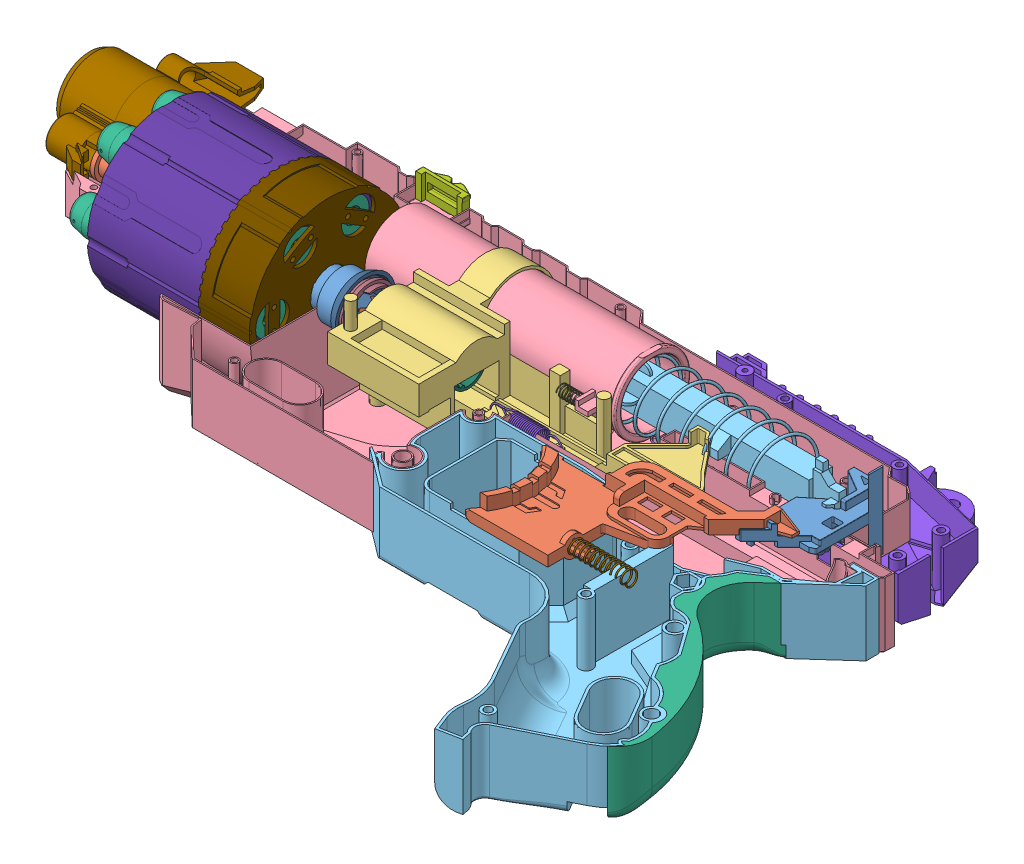
SolidWorks assembly FullAssembly, configuration Default. Lengths in mm.
Overall size (323.71 84.54 189).
50 component instances, 33 part files, 65 mates.
Components (placement in the parent):
- Casing Assembly-1: Casing Assembly [Default] at (151.4188 153.405 192.5829) size (316.26 35.4 180.45)
  - BlueCasing-1: BlueCasing [Default] at (-617.0884 -4.4748 593.468) size (308.07 35.4 103.82) (hidden)
  - Light Grey Handle-1: Light Grey Handle [Default] at (-617.0884 -4.4748 593.468) x (1 0 0) z (0 1 0) size (148.12 135.48 25.59) (hidden)
  - DarkGreyHandle-1: DarkGreyHandle [Default] at (-617.0884 -4.4748 593.468) x (1 0 0) z (0 1 0) size (51.4 89.36 25.17) (hidden)
- NerfPart1-1: NerfPart1 [Default] at (249.0248 148.9301 159.2025) x (0 0 1) z (0 1 0) size (41.76 19.13 29)
- NerfPart2-1: NerfPart2 [Default] at (217.0076 150.9301 223.4293) x (1 0 0) z (0 1 0) size (77.26 55.51 14)
- carrier assy-1: carrier assy [Default] at (183.9347 126.8386 117.2142) x (0 1 0) z (0 0 1) size (39.22 174.51 65.1)
  - Carrier-1: Carrier [Default] at (22.0915 43.5029 51.6249) size (39.22 83.08 65.1)
  - Nerf cylinder-1: Nerf cylinder [Default] at (22.0915 2.6203 51.6249) x (0 0 -1) z (0 1 0) size (34.5 28.93 100.29)
  - Piston-2: Piston [Default] at (22.0915 23.114 51.6249) x (1 0 0) z (0 -1 0) size (25 25 95)
- NerfDart-1: NerfDart [Default] at (82.2606 167.1322 185.1965) x (0 -0.202966 -0.979186) z (0 0.979186 -0.202966) size (12.8 72.8 12.8)
- Sights-1: Sights [Default] at (84.1794 153.5301 143.1658) x (-0.99995 0 -0.009952) z (0 -1 0) size (18.4 11.6 9.2)
- Slider1-1: Slider1 [Default] at (288.3635 131.9301 181.5662) x (-1 0 0) z (0 -1 0) size (112.73 46.9 27)
- Tip-1: Tip [Default] at (-6.6716 148.9301 175.5592) x (0 -1 0) z (-1 0 0) size (27.76 65.59 33.8)
- Cylinder_Rotator-1: Cylinder_Rotator [Default] at (80.8973 165.6762 224.1879) x (0 0.418707 -0.908121) z (0 -0.908121 -0.418707) size (25.03 47.62 25.04)
  - Cylinder_Rotator_pt1-1: Cylinder_Rotator_pt1 [Default] at (18.8958 8.6532 27.1526) size (23.17 32.6 23.17)
  - Cylinder_Rotator_pt2-1: Cylinder_Rotator_pt2 [Default] at (18.8958 18.6132 27.1526) x (-0.510192 0 -0.860061) z (0.860061 0 -0.510192) size (10.13 14.17 10.13)
  - Cylinder_Rotator_Spring-1: Cylinder_Rotator_Spring [Default] at (19.0112 24.4693 27.2364) size (6.17 17.01 6.17)
  - Cylinder_Rotator_Ring-1: Cylinder_Rotator_Ring [Default] at (18.8958 15.2032 27.1526) x (-0.990155 0 0.139974) z (-0.139974 0 -0.990155) size (19.4 5.35 19.23)
  - Cylinder_Rotator_Screw-1: Cylinder_Rotator_Screw [Default] at (18.8943 33.5132 27.1524) x (-0.438039 0 0.898956) z (-0.898956 0 -0.438039) size (6.55 9.42 6.55)
  - Cylinder_Rotator_pt3-1: Cylinder_Rotator_pt3 [Default] at (18.9009 56.2732 27.1494) x (-0.691686 0 -0.722198) z (-0.722198 0 0.691686) size (17.88 16.85 17.54)
  - Cylinder_Rotator_pt4-1: Cylinder_Rotator_pt4 [Default] at (18.8958 21.5032 27.1526) x (0.960127 0 0.279563) z (-0.279563 0 0.960127) size (19.34 22.93 19.73)
- CylinderAssembly-1: CylinderAssembly [Default] at (100.9463 106.9885 231.6989) x (0 -0.498348 -0.866977) z (0 0.866977 -0.498348) size (61.92 96.59 61.91)
  - Cylinder_TopHalf-1: Cylinder_TopHalf [Default] at (10.3441 36.2557 54.3227) size (61.26 74 61.24)
  - Cylinder_BottomHalf-1: Cylinder_BottomHalf [Default] at (10.3441 17.2957 54.3227) x (-0.999941 0 0.010888) z (-0.010888 0 -0.999941) size (61.26 49.19 61.25)
  - Cylinder_BottomLock-1: Cylinder_BottomLock [Default] at (10.3441 6.3257 54.3227) x (0.135612 0 0.990762) z (-0.990762 0 0.135612) size (32 44 30.63)
  - Cylinder_TopLock-1: Cylinder_TopLock [Default] at (10.3441 102.9157 54.3227) x (0.024849 0 0.999691) z (0.999691 0 -0.024849) size (12.51 52.56 12.51)
- NerfDart-2: NerfDart [Default] at (82.2606 167.0921 206.1913) x (0 -1 0) z (0 0 -1) size (12.8 72.8 12.8)
- NerfDart-3: NerfDart [Default] at (82.2606 148.8901 216.654) x (0 -1 0) z (0 0 -1) size (12.8 72.8 12.8)
- NerfDart-4: NerfDart [Default] at (82.2606 130.7681 185.1272) x (0 -0.675813 0.737073) z (0 -0.737073 -0.675813) size (12.8 72.8 12.8)
- NerfDart-5: NerfDart [Default] at (82.2606 148.9702 174.6644) x (0 -1 0) z (0 0 -1) size (12.8 72.8 12.8)
- NerfDart-6: NerfDart [Default] at (82.2606 130.7281 206.1219) x (0 -0.659658 0.751566) z (0 -0.751566 -0.659658) size (12.8 72.8 12.8)
- Slider Mirrored-1: Slider Mirrored [Default] at (288.3635 136.9301 181.5706) x (-1 0 0) z (0 -1 0) size (112.73 46.9 20.4) (hidden)
- NerfPart3-reexport-1: NerfPart3-reexport [Default] at (119.2158 139.9393 195.9682) x (1 0 0) z (0 0 -1) size (111.39 22 27.4)
- BlueCaseMirrored-1: BlueCaseMirrored [Default] at (-465.6697 148.9301 786.0466) size (308.07 35.4 103.82)
- LightGreyHandleMirrored-1: LightGreyHandleMirrored [Default] at (-465.6697 144.9301 786.0466) x (1 0 0) z (0 1 0) size (148.12 135.48 25.59)
- DarkGreyHandleMirrored-1: DarkGreyHandleMirrored [Default] at (-465.6697 148.9301 786.0466) x (1 0 0) z (0 1 0) size (51.4 89.36 25.17)
- Carrier spring-1: Carrier spring [Default] at (163.6115 150.4292 186.241) x (0 0 -1) z (1 0 0) size (4.51 4.51 7.75)
- TensionSpring-1: TensionSpring [Default] at (170.4562 144.9876 200.8512) x (0 1 0) z (0 0 1) size (8.08 27.82 7.01)
- TensionSpring-2: TensionSpring [Default] at (202.0156 136.5451 169.4754) x (0 0 1) z (0 -1 0) size (8.08 27.82 7.01)
- MiscSpring-1: MiscSpring [Default] at (239.1597 149.1566 234.3892) x (0 0 -1) z (0 1 0) size (6.12 23.1 6.41)
- MiscSpring2-1: MiscSpring2 [Default] at (261.1789 145.7119 163.4853) x (1 0 0) z (0 -1 0) size (4.53 23.09 4.73)
- 3mmScrew-1: 3mmScrew [Default] at (4.8684 148.2102 207.3086) x (-0.764362 0 -0.644787) z (0.644787 0 -0.764362) size (4 8.2 4) (hidden)
- 3mmScrew-2: 3mmScrew [Default] at (219.7975 165.9301 215.9458) size (4 8.2 4) (hidden)
- 3mmScrew-3: 3mmScrew [Default] at (254.5717 165.9301 305.3686) size (4 8.2 4) (hidden)
- 3mmScrew-4: 3mmScrew [Default] at (234.7726 165.9301 247.919) size (4 8.2 4) (hidden)
- 3mmScrew-5: 3mmScrew [Default] at (89.4505 165.9301 237.8602) size (4 8.2 4) (hidden)
- 3mmScrew-6: 3mmScrew [Default] at (145.9645 157.9301 145.8722) size (4 8.2 4) (hidden)
- 3mmScrew-7: 3mmScrew [Default] at (-9.6881 165.9301 153.5914) size (4 8.2 4) (hidden)
- 3mmScrew-8: 3mmScrew [Default] at (43.7549 155.9301 144.8568) size (4 8.2 4) (hidden)
Mates (geometry in assembly coordinates):
- Coincident1: coincident anti-aligned: plane of Casing Assembly-1/BlueCasing-1 through (87.9306 173.9301 215.0121) normal (1 0 0); plane of CylinderAssembly-1/Cylinder_BottomLock-1 through (87.9306 148.9301 195.6592) normal (-1 0 0)
- Concentric3: concentric anti-aligned: circle of Casing Assembly-1/BlueCasing-1; circle of CylinderAssembly-1/Cylinder_BottomLock-1
- Concentric4: concentric aligned: circle of NerfDart-1; circle of CylinderAssembly-1/Cylinder_TopHalf-1
- Coincident3: coincident anti-aligned: plane of NerfDart-1 through (82.2606 167.1322 185.1965) normal (1 0 0); plane of CylinderAssembly-1/Cylinder_BottomHalf-1 through (82.2606 148.9301 195.6592) normal (-1 0 0)
- Concentric5: concentric aligned: circle of CylinderAssembly-1/Cylinder_TopHalf-1; circle of NerfDart-2
- Concentric7: concentric aligned: circle of CylinderAssembly-1/Cylinder_TopHalf-1; circle of NerfDart-3
- Concentric8: concentric aligned: circle of CylinderAssembly-1/Cylinder_TopHalf-1; circle of NerfDart-6
- Concentric9: concentric aligned: circle of CylinderAssembly-1/Cylinder_TopHalf-1; circle of NerfDart-4
- Concentric10: concentric aligned: circle of CylinderAssembly-1/Cylinder_TopHalf-1; circle of NerfDart-5
- Coincident4: coincident aligned: plane of CylinderAssembly-1/Cylinder_BottomHalf-1 through (82.2606 148.9301 195.6592) normal (-1 0 0); circle of NerfDart-5
- Coincident5: coincident anti-aligned: plane of CylinderAssembly-1/Cylinder_BottomHalf-1 through (82.2606 148.9301 195.6592) normal (-1 0 0); plane of NerfDart-4 through (82.2606 130.7681 185.1272) normal (1 0 0)
- Coincident6: coincident anti-aligned: plane of CylinderAssembly-1/Cylinder_BottomHalf-1 through (82.2606 148.9301 195.6592) normal (-1 0 0); plane of NerfDart-6 through (82.2606 130.7281 206.1219) normal (1 0 0)
- Coincident7: coincident anti-aligned: plane of CylinderAssembly-1/Cylinder_BottomHalf-1 through (82.2606 148.9301 195.6592) normal (-1 0 0); plane of NerfDart-2 through (82.2606 167.0921 206.1913) normal (1 0 0)
- Coincident8: coincident aligned: plane of CylinderAssembly-1/Cylinder_BottomHalf-1 through (82.2606 148.9301 195.6592) normal (-1 0 0); circle of NerfDart-3
- Coincident9: coincident aligned: plane of Cylinder_Rotator-1/Cylinder_Rotator_pt1-1 through (94.6206 148.9301 195.6592) normal (-1 0 0); circle of CylinderAssembly-1/Cylinder_BottomLock-1
- Concentric11: concentric anti-aligned: circle of Cylinder_Rotator-1/Cylinder_Rotator_pt1-1; circle of CylinderAssembly-1/Cylinder_BottomLock-1
- Lock1: lock: unknown of Cylinder_Rotator-1/Cylinder_Rotator_pt3-1; unknown of CylinderAssembly-1/Cylinder_BottomLock-1
- Concentric16: concentric anti-aligned: cylinder of Tip-1 through (-18.4716 148.9301 195.6592) axis (1 0 0) radius 5.1; cylinder of CylinderAssembly-1/Cylinder_TopLock-1 through (6.8506 148.9301 195.6592) axis (-1 0 0) radius 3.47
- Parallel6: parallel aligned: plane of Casing Assembly-1/BlueCasing-1 through (8.236 173.9301 145.9317) normal (0 0 -1); plane of Tip-1 through (-13.9716 148.9301 139.9688) normal (0 0 -1)
- Lock3: lock: unknown of Casing Assembly-1/BlueCasing-1; unknown of Tip-1
- Coincident18: coincident anti-aligned: plane of Casing Assembly-1/Light Grey Handle-1 through (-465.6695 150.9301 786.0509) normal (0 -1 0); plane of NerfPart2-1 through (217.0076 150.9301 223.4293) normal (0 1 0)
- Distance1: distance = 0.6764 mm aligned: plane of Casing Assembly-1/Light Grey Handle-1 through (207.5765 173.9301 210.6382) normal (0 0 -1); plane of NerfPart2-1 through (217.0076 146.9301 209.9618) normal (0 0 -1)
- Coincident21: coincident anti-aligned: plane of Casing Assembly-1/BlueCasing-1 through (263.4079 173.9301 152.0403) normal (1 0 0); plane of NerfPart1-1 through (263.4079 163.4301 159.2025) normal (-1 0 0)
- Parallel8: parallel aligned: plane of Casing Assembly-1/BlueCasing-1 through (153.8033 148.9301 208.3008) normal (0 -1 0); plane of NerfPart1-1 through (249.0248 134.4301 159.2025) normal (0 -1 0)
- Parallel9: parallel anti-aligned: plane of Casing Assembly-1/BlueCasing-1 through (153.8033 173.4301 208.3008) normal (0 -1 0); plane of NerfPart3-reexport-1 through (119.2158 139.9393 195.9682) normal (0 1 0)
- Parallel11: parallel anti-aligned: plane of Casing Assembly-1/BlueCasing-1 through (192.4434 173.9301 205.4079) normal (0 0 -1); plane of NerfPart3-reexport-1 through (119.2158 150.9393 199.4682) normal (0 0 1)
- Distance5: distance = 31.4909 mm anti-aligned: plane of Casing Assembly-1/BlueCasing-1 through (153.8033 173.4301 208.3008) normal (0 -1 0); plane of NerfPart3-reexport-1 through (119.2158 141.9393 195.9682) normal (0 1 0)
- Concentric19: concentric anti-aligned: cylinder of Tip-1 through (-28.4716 148.9301 175.5592) axis (1 0 0) radius 13.7; cylinder of BlueCaseMirrored-1 through (23.9779 148.9301 175.5592) axis (-1 0 0) radius 13.7
- Coincident41: coincident aligned: plane of Casing Assembly-1/BlueCasing-1 through (-16.2678 173.9301 190.0507) normal (-0.999236 0 0.039083); plane of BlueCaseMirrored-1 through (-16.2679 123.9301 190.0463) normal (-0.999236 0 0.039083)
- Coincident43: coincident anti-aligned: plane of Casing Assembly-1/Light Grey Handle-1 through (217.173 148.9301 266.6939) normal (0 -1 0); plane of LightGreyHandleMirrored-1 through (217.1728 148.9301 266.6895) normal (0 1 0)
- Coincident44: coincident aligned: line of BlueCaseMirrored-1 through (240.6111 125.9301 202.9035) axis (-1 0 0); line of LightGreyHandleMirrored-1 through (240.6111 125.9301 202.9035) axis (-1 0 0)
- Coincident45: coincident aligned: line of BlueCaseMirrored-1 through (144.5745 125.9301 209.9854) axis (0 0 1); line of LightGreyHandleMirrored-1 through (144.5745 125.9301 209.9854) axis (0 0 1)
- Coincident52: coincident anti-aligned: plane of Casing Assembly-1/BlueCasing-1 through (-465.6695 151.4301 786.0509) normal (0 1 0); plane of Slider Mirrored-1 through (286.9635 151.4301 179.8706) normal (0 -1 0)
- Coincident54: coincident anti-aligned: plane of Slider1-1 through (286.9635 146.4301 179.8662) normal (0 1 0); plane of BlueCaseMirrored-1 through (-465.6697 146.4301 786.0466) normal (0 -1 0)
- Coincident57: coincident anti-aligned: plane of Slider1-1 through (288.3635 131.9301 181.5662) normal (0 0 1); plane of BlueCaseMirrored-1 through (197.7633 148.9301 181.5662) normal (0 0 -1)
- Coincident58: coincident aligned: line of Slider1-1 through (288.3635 148.9301 169.1418) axis (0 0 1); line of Slider Mirrored-1 through (288.3635 148.9301 169.1462) axis (0 0 1)
- Coincident59: coincident anti-aligned: plane of LightGreyHandleMirrored-1 through (273.378 128.4301 275.6246) normal (0 -1 0); plane of DarkGreyHandleMirrored-1 through (292.1935 128.4301 290.6663) normal (0 1 0)
- Concentric20: concentric aligned: cylinder of LightGreyHandleMirrored-1 through (273.2169 123.9301 275.7157) axis (0 1 0) radius 13.4824; cylinder of DarkGreyHandleMirrored-1 through (273.2169 128.4301 275.7157) axis (0 1 0) radius 13.4824
- Coincident60: coincident aligned: line of Sights-1 through (83.8914 145.8801 141.9628) axis (0 1 0); line of BlueCaseMirrored-1 through (83.8914 145.8801 141.9628) axis (0 1 0)
- Coincident61: coincident aligned: line of Sights-1 through (65.9923 144.3301 141.7847) axis (0.99995 0 0.009952); line of BlueCaseMirrored-1 through (79.2685 144.3301 141.9168) axis (0.99995 0 0.009952)
- Concentric21: concentric anti-aligned: circle of carrier assy-1/Carrier-1; circle of Cylinder_Rotator-1/Cylinder_Rotator_pt1-1
- Lock4: lock: unknown of carrier assy-1/Carrier-1; unknown of BlueCaseMirrored-1
- Distance8: distance = 2 mm aligned: plane of NerfPart1-1 through (249.0248 150.9301 159.2025) normal (0 1 0); plane of BlueCaseMirrored-1 through (153.8031 148.9301 208.2964) normal (0 1 0)
- Lock6: lock: unknown of carrier assy-1/Nerf cylinder-1; unknown of Carrier spring-1
- Lock8: lock: unknown of carrier assy-1/Carrier-1; unknown of TensionSpring-1
- Distance9: distance = 15.1453 mm: line of NerfPart3-reexport-1 through (146.2158 141.9393 192.4682) axis (1 0 0); line of LightGreyHandleMirrored-1 through (157.3069 148.9301 205.9035) axis (1 0 0)
- Lock10: lock: unknown of BlueCaseMirrored-1; unknown of TensionSpring-2
- Lock11: lock: unknown of NerfPart2-1; unknown of MiscSpring-1
- Lock14: lock: unknown of NerfPart1-1; unknown of MiscSpring2-1
- Concentric22: concentric aligned: circle of Casing Assembly-1/Light Grey Handle-1; circle of 3mmScrew-4
- Coincident62: coincident aligned: plane of Casing Assembly-1/Light Grey Handle-1 through (217.173 173.9301 266.6939) normal (0 1 0); plane of 3mmScrew-4 through (234.7726 173.9301 247.919) normal (0 1 0)
- Concentric23: concentric aligned: circle of Casing Assembly-1/Light Grey Handle-1; circle of 3mmScrew-3
- Coincident63: coincident aligned: plane of Casing Assembly-1/Light Grey Handle-1 through (217.173 173.9301 266.6939) normal (0 1 0); plane of 3mmScrew-3 through (254.5717 173.9301 305.3686) normal (0 1 0)
- Concentric24: concentric aligned: circle of Casing Assembly-1/Light Grey Handle-1; circle of 3mmScrew-2
- Coincident64: coincident aligned: plane of Casing Assembly-1/Light Grey Handle-1 through (217.173 173.9301 266.6939) normal (0 1 0); plane of 3mmScrew-2 through (219.7975 173.9301 215.9458) normal (0 1 0)
- Coincident67: coincident anti-aligned: plane of Casing Assembly-1/BlueCasing-1 through (197.7635 148.9301 181.5706) normal (0 0 -1); plane of Slider Mirrored-1 through (288.3635 165.9301 181.5706) normal (0 0 1)
- Concentric25: concentric aligned: circle of Casing Assembly-1/BlueCasing-1; circle of 3mmScrew-5
- Coincident68: coincident aligned: plane of Casing Assembly-1/BlueCasing-1 through (153.8033 173.9301 208.3008) normal (0 1 0); plane of 3mmScrew-5 through (89.4505 173.9301 237.8602) normal (0 1 0)
- Concentric26: concentric anti-aligned: cylinder of Casing Assembly-1/BlueCasing-1 through (4.8684 148.9301 207.3086) axis (0 1 0) radius 1.1; cylinder of 3mmScrew-1 through (4.8684 155.2102 207.3086) axis (0 -1 0) radius 1.4
- Concentric27: concentric aligned: circle of Casing Assembly-1/BlueCasing-1; circle of 3mmScrew-7
- Coincident69: coincident aligned: plane of Casing Assembly-1/BlueCasing-1 through (153.8033 173.9301 208.3008) normal (0 1 0); plane of 3mmScrew-7 through (-9.6881 173.9301 153.5914) normal (0 1 0)
- Concentric28: concentric aligned: circle of Casing Assembly-1/BlueCasing-1; circle of 3mmScrew-6
- Coincident70: coincident aligned: plane of Casing Assembly-1/BlueCasing-1 through (-465.6695 165.9301 786.0509) normal (0 1 0); plane of 3mmScrew-6 through (145.9645 165.9301 145.8722) normal (0 1 0)
- Concentric29: concentric anti-aligned: circle of Casing Assembly-1/BlueCasing-1; circle of 3mmScrew-8
- Coincident71: coincident aligned: plane of Casing Assembly-1/BlueCasing-1 through (-465.6695 163.9301 786.0509) normal (0 1 0); plane of 3mmScrew-8 through (43.7549 163.9301 144.8568) normal (0 1 0)
